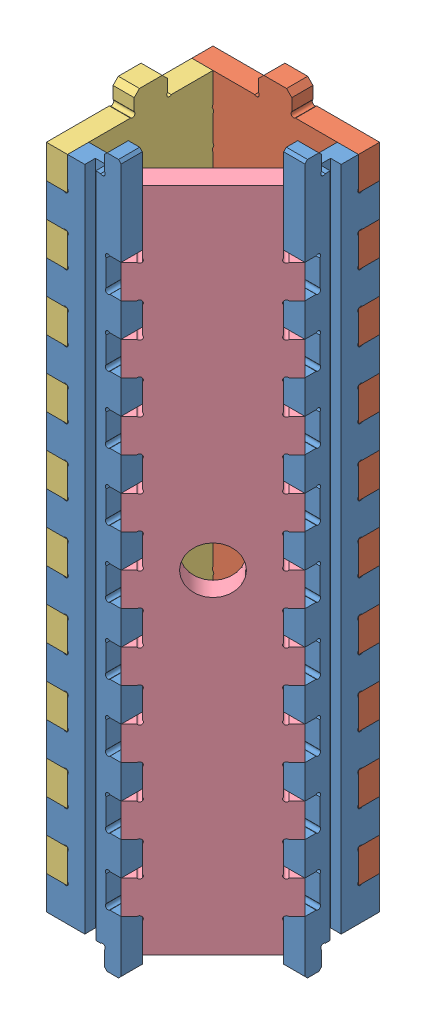
SolidWorks assembly columns_assembly02, configuration Default. Lengths in mm.
Overall size (50 212.7 50).
5 component instances, 4 part files, 13 mates.
Components (placement in the parent):
- columns03-1: columns03 [a] at (-70.7593 -80.1229 14.7397) size (22.44 212.7 6.35)
- columns03-2: columns03 [b] at (-20.7593 -80.1229 -28.9103) x (0 0 1) z (-1 0 0) size (22.44 212.7 6.35)
- columns02-1: columns02 [Default] at (-27.1093 -80.1229 -22.5603) x (-1 0 0) z (0 0 -1) size (50 212.7 6.35)
- columns01-1: columns01 [Default] at (-64.4093 -80.1229 -28.9103) x (0 0 1) z (-1 0 0) size (50 212.7 6.35)
- pvc-250-column04-1: pvc-250-column04 [Default] at (-49.6377 119.8771 13.4246) x (0 -1 0) z (0.707107 0 0.707107) size (200 38.98 6.35)
Mates (geometry in assembly coordinates):
- Coincident1: coincident: plane of assembly; plane of assembly; plane of columns02-1 through (-64.4093 100.9996 -28.9103) normal (-1 0 0); plane of columns01-1 through (-64.4093 9.3158 15.301) normal (1 0 0)
- Coincident2: coincident: plane of assembly; plane of assembly; plane of columns02-1 through (-70.7593 119.8771 -28.9103) normal (0 1 0); plane of columns01-1 through (-70.7593 119.8771 14.7397) normal (0 1 0)
- Coincident3: coincident: plane of assembly; plane of assembly; plane of columns02-1 through (-26.5481 109.2645 -28.9103) normal (0 0 -1); plane of columns01-1 through (-70.7593 109.8771 -28.9103) normal (0 0 -1)
- Coincident5: coincident: plane of assembly; plane of assembly; plane of columns03-2 through (-27.1093 70.4383 -10.4023) normal (-1 0 0); plane of columns02-1 through (-27.1093 108.7032 -28.9103) normal (1 0 0)
- Coincident6: coincident: plane of assembly; plane of assembly; plane of columns03-2 through (-27.1093 119.8771 -22.5603) normal (0 1 0); plane of columns02-1 through (-39.6368 119.8771 -28.9103) normal (0 1 0)
- Coincident7: coincident: plane of assembly; plane of assembly; plane of columns03-2 through (-27.1093 99.8771 -28.9103) normal (0 0 -1); plane of columns02-1 through (-26.5481 109.2645 -28.9103) normal (0 0 -1)
- Coincident8: coincident: plane of assembly; plane of assembly; plane of columns03-1 through (-52.2514 70.4383 14.7397) normal (0 0 -1); plane of columns01-1 through (-70.7593 100.9996 14.7397) normal (0 0 1)
- Coincident9: coincident: plane of assembly; plane of assembly; plane of columns03-1 through (-64.4093 119.8771 21.0897) normal (0 1 0); plane of columns01-1 through (-70.7593 119.8771 14.7397) normal (0 1 0)
- Coincident10: coincident: plane of assembly; plane of assembly; plane of columns03-1 through (-70.7593 99.8771 21.0897) normal (-1 0 0); plane of columns01-1 through (-70.7593 9.3158 15.301) normal (-1 0 0)
- Coincident21: coincident: plane of assembly; plane of assembly; plane of columns03-2 through (-27.1093 89.8771 -9.8411) normal (0 1 0); plane of pvc-250-column04-1 through (-48.3225 89.8771 21.0897) normal (0 -1 0)
- Coincident22: coincident: plane of assembly; line of assembly; plane of columns03-2 through (-27.1093 98.7545 -10.9636) normal (0 0 1); line of pvc-250-column04-1 through (-25.2494 89.9533 -10.9636) axis (0 1 0)
- Coincident23: coincident: plane of assembly; line of assembly; plane of columns03-1 through (-52.8127 98.7545 21.0897) normal (1 0 0); line of pvc-250-column04-1 through (-52.8127 99.8771 16.5996) axis (0 -1 0)
- Angle4: planar angle = 0.785398 rad: plane of assembly; plane of assembly; plane of columns02-1 through (-26.5481 109.2645 -22.5603) normal (0 0 1); plane of pvc-250-column04-1 through (-50.0345 -70.6842 13.8215) normal (-0.707107 0 -0.707107)
